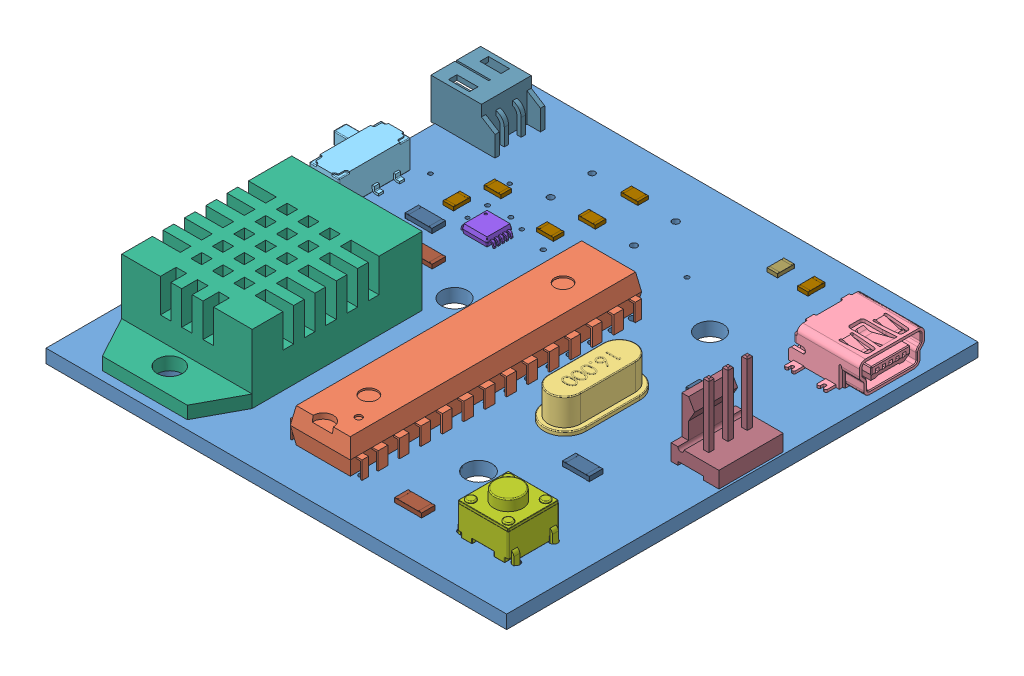
SolidWorks assembly PCB_Assembly, configuration Default. Lengths in mm.
Overall size (56.64 13.4 55.88).
22 component instances, 14 part files, 0 mates.
Components (placement in the parent):
- PCB_Model-2: PCB_Model [Default] at (-31.7995 47.3987 0.7701) x (1 0 0) z (0 0 -1) size (54.61 1.6 55.88)
- ATMega328-1: ATMega328 [Default] at (-31.0377 49.5031 6.9913) x (0 0 -1) z (1 0 0) size (34.54 7.64 8.52)
- crystal-1: crystal [Default] at (-21.0528 47.3757 2.0479) x (0 0 -1) z (0 -1 0) size (11.35 5 7.69)
- USB_B_mini-1: USB_B_mini [Standard] at (-4.7975 49.4613 -17.8726) x (0 0 -1) z (1 0 0) size (10 3.96 8.9)
- SMD_switch-1: SMD_switch [Default] at (-57.3857 47.5063 -6.7984) x (0 0 1) z (-1 0 0) size (8.5 3.5 6.25)
- DHT22-1: DHT22 [Default] at (-48.4144 47.3723 15.1132) x (0 1 0) z (1 0 0) size (8.15 28.1 15.47)
- tactileswitch-1: tactileswitch [Default] at (-12.3253 47.5004 20.6807) size (7.69 8.33 6.01)
- battery_manamagement_unit-1: battery_manamagement_unit [Default] at (-44.6982 47.2987 -9.166) size (3.9 1.13 3)
- RES805-1: RES805 [0805] at (-48.4595 47.6061 -14.203) size (2 0.45 1.26)
- RES805-2: RES805 [0805] at (-49.6495 47.6061 -10.5201) x (0 0 -1) z (1 0 0) size (2 0.45 1.26)
- RES805-3: RES805 [0805] at (-40.9731 47.5859 -12.9434) size (2 0.45 1.26)
- RES805-4: RES805 [0805] at (-39.6599 47.5657 -21.6308) size (2 0.45 1.26)
- RES805-5: RES805 [0805] at (-39.7476 47.6061 -16.6763) size (2 0.45 1.26)
- RES805-6: RES805 [0805] at (-19.8807 47.6136 -22.7752) x (0 0 -1) z (1 0 0) size (2 0.45 1.26)
- RES1206-1: RES1206 [1206] at (-14.779 47.6657 9.4251) size (3.2 0.55 1.61)
- RES1206-3: RES1206 [1206] at (-15.0667 47.6416 -5.5236) size (3.2 0.55 1.61)
- CAP1206-1: CAP1206 [1206] at (-45.9303 47.6135 -3.097) size (3.2 0.55 1.61)
- CAP1206-2: CAP1206 [1206] at (-20.9877 47.6461 23.095) size (3.2 0.55 1.61)
- RES1206-4: RES1206 [1206] at (-49.5706 47.6634 -6.7164) size (3.2 0.55 1.61)
- LED805-1: LED805 [0805] at (-23.5729 47.606 -22.8499) x (0 0 -1) z (1 0 0) size (2 0.45 1.26)
- 3-Pin Fan Header-2: 3-Pin Fan Header [Default] at (-4.7461 47.3226 5.8379) x (0 0 -1) z (1 0 0) size (7.63 9.45 5.66)
- connector-1: connector [S2B-PH-K-S] at (-53.5911 49.7301 -20.355) x (0 0 1) z (-1 0 0) size (5.9 6.8 7.6)
